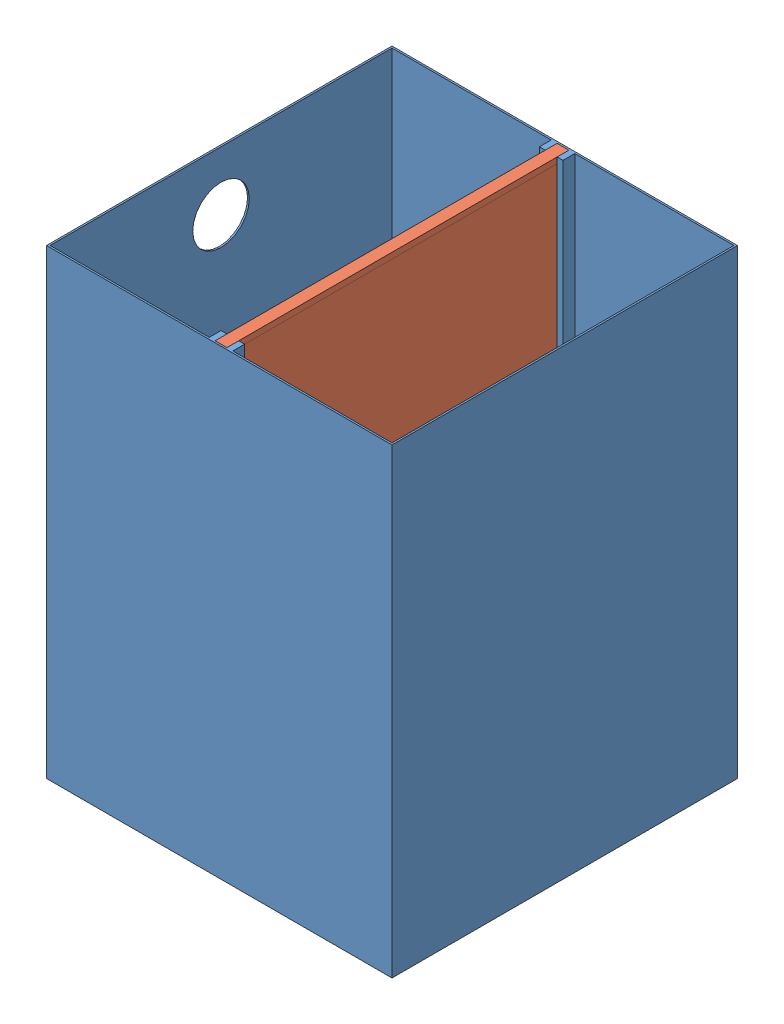
SolidWorks assembly tank, configuration Default. Lengths in mm.
Overall size (293 391.5 293).
3 component instances, 3 part files, 6 mates.
Components (placement in the parent):
- tank body-1: tank body [Default] at (179.7119 -13.0067 297.4419) size (293 391.5 293)
- mesh screen-1: mesh screen [Default] at (174.7119 183.4933 297.4419) x (0 0 -1) z (1 0 0) size (290 390 10)
- pump-1: pump [Default] at (256.3156 -11.5067 244.2264) size (80 105 120)
Mates (geometry in assembly coordinates):
- Coincident1: coincident anti-aligned: plane of tank body-1 through (184.7119 -1.5067 297.4419) normal (-1 0 0); plane of mesh screen-1 through (184.7119 183.4933 297.4419) normal (1 0 0)
- Coincident2: coincident anti-aligned: plane of tank body-1 through (33.2119 378.4933 152.4419) normal (0 0 1); plane of mesh screen-1 through (184.7119 378.4933 152.4419) normal (0 0 -1)
- Coincident3: coincident aligned: plane of tank body-1 through (179.7119 378.4933 297.4419) normal (0 1 0); plane of mesh screen-1 through (184.7119 378.4933 442.4419) normal (0 1 0)
- Coincident4: coincident anti-aligned: plane of tank body-1 through (179.7119 -11.5067 297.4419) normal (0 1 0); plane of pump-1 through (256.3156 -11.5067 244.2264) normal (0 -1 0)
- LimitDistance1: limit distance = 28.3963 mm anti-aligned: plane of pump-1 through (296.3156 88.4933 184.2264) normal (1 0 0); plane of tank body-1 through (324.7119 378.4933 150.9419) normal (-1 0 0)
- LimitDistance2: limit distance = 138.2155 mm anti-aligned: plane of pump-1 through (216.3156 88.4933 304.2264) normal (0 0 1); plane of tank body-1 through (33.2119 378.4933 442.4419) normal (0 0 -1)
